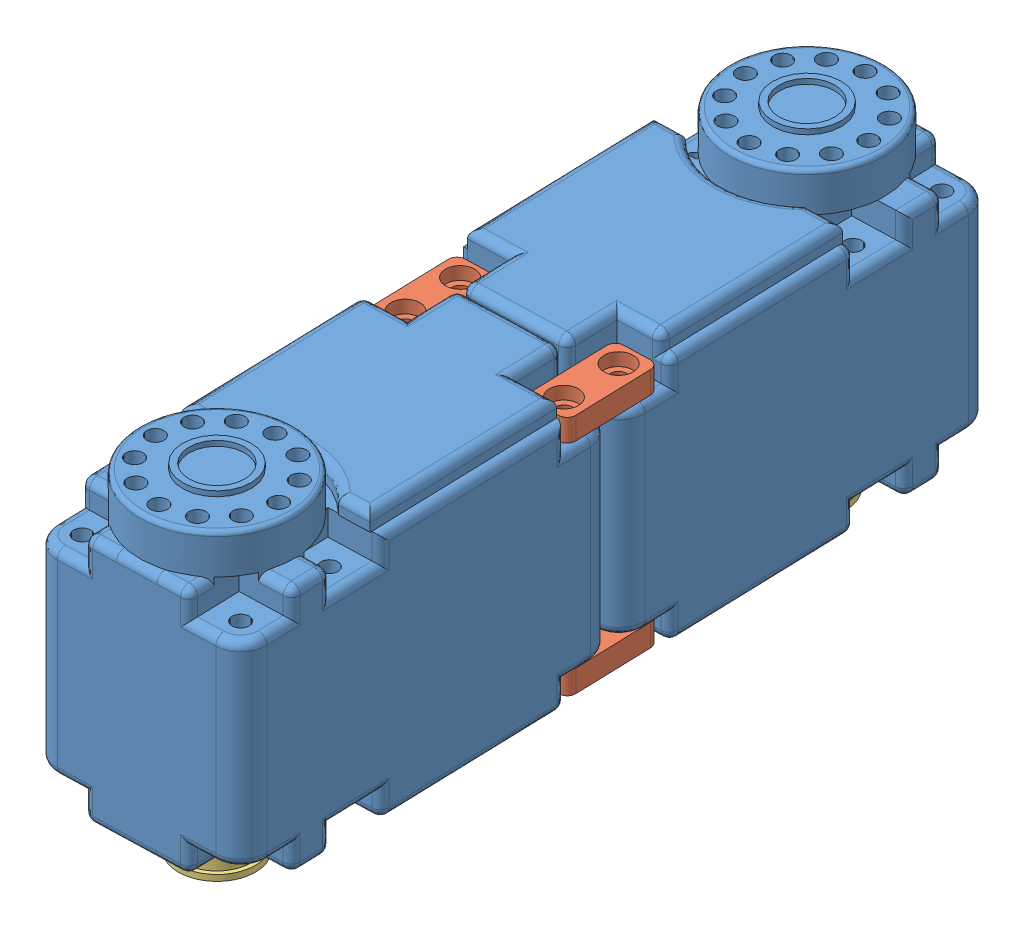
SolidWorks assembly arm, configuration Default. Lengths in mm.
Overall size (26.73 39.2 91.28).
8 component instances, 3 part files, 18 mates.
Components (placement in the parent):
- herkulex_motor-1: herkulex_motor [Default] at (3.1521 53.1425 38.0968) x (0.999543 0 -0.030221) z (0.030221 0 0.999543) size (24 34.2 45)
- line loint-1: line loint [Default] at (12.8371 53.5425 60.6144) x (-0.030221 0 -0.999543) z (0.999543 0 -0.030221) size (11 2.6 5)
- line loint-2: line loint [Default] at (-5.1547 53.5425 61.1584) x (-0.030221 0 -0.999543) z (0.999543 0 -0.030221) size (11 2.6 5)
- line loint-3: line loint [Default] at (12.8371 79.1425 60.6144) x (-0.030221 0 -0.999543) z (0.999543 0 -0.030221) size (11 2.6 5)
- line loint-4: line loint [Default] at (-5.1547 79.1425 61.1584) x (-0.030221 0 -0.999543) z (0.999543 0 -0.030221) size (11 2.6 5)
- support-1: support [Default] at (2.7653 53.6425 25.3027) x (0 -1 0) z (0 0 1) size (5.5 9 9)
- herkulex_motor-3: herkulex_motor [Default] at (4.5302 53.1425 83.676) x (-0.999543 0 0.030221) z (-0.030221 0 -0.999543) size (24 34.2 45)
- support-2: support [Default] at (4.917 53.6425 96.4701) x (0 -1 0) z (0 0 1) size (5.5 9 9)
Mates (geometry in assembly coordinates):
- Concentric1: concentric aligned: cylinder of herkulex_motor-1 through (12.7373 53.1425 57.3159) axis (0 1 0) radius 1; cylinder of line loint-1 through (12.7373 54.6425 57.3159) axis (0 1 0) radius 1.7
- Coincident4: coincident anti-aligned: plane of herkulex_motor-1 through (3.1521 56.1425 38.0968) normal (0 -1 0); plane of line loint-1 through (12.8371 56.1425 60.6144) normal (0 1 0)
- Concentric3: concentric anti-aligned: cylinder of herkulex_motor-1 through (-5.2545 53.1425 57.8599) axis (0 1 0) radius 1; cylinder of line loint-2 through (-5.2545 56.1425 57.8599) axis (0 -1 0) radius 1
- Coincident5: coincident anti-aligned: plane of herkulex_motor-1 through (3.1521 56.1425 38.0968) normal (0 -1 0); plane of line loint-2 through (-5.1547 56.1425 61.1584) normal (0 1 0)
- Concentric5: concentric aligned: cylinder of herkulex_motor-1 through (12.7373 53.1425 57.3159) axis (0 1 0) radius 1; cylinder of line loint-3 through (12.7373 80.2425 57.3159) axis (0 1 0) radius 1.7
- Coincident6: coincident anti-aligned: plane of herkulex_motor-1 through (3.1521 79.1425 38.0968) normal (0 1 0); plane of line loint-3 through (12.8371 79.1425 60.6144) normal (0 -1 0)
- Concentric7: concentric aligned: cylinder of herkulex_motor-1 through (-5.2545 53.1425 57.8599) axis (0 1 0) radius 1; cylinder of line loint-4 through (-5.2545 80.2425 57.8599) axis (0 1 0) radius 1.7
- Coincident7: coincident anti-aligned: plane of herkulex_motor-1 through (3.1521 79.1425 38.0968) normal (0 1 0); plane of line loint-4 through (-8.0335 79.1425 59.6395) normal (0 -1 0)
- Coincident8: coincident anti-aligned: plane of herkulex_motor-1 through (2.7653 53.6425 25.3027) normal (0 -1 0); plane of support-1 through (2.7653 53.6425 25.3027) normal (0 1 0)
- Concentric8: concentric aligned: circle of herkulex_motor-1; cylinder of support-1 through (2.7653 50.1425 25.3027) axis (0 -1 0) radius 2.7
- Concentric9: concentric aligned: cylinder of line loint-2 through (-5.055 54.6425 64.4569) axis (0 1 0) radius 1.7; cylinder of herkulex_motor-3 through (-5.055 53.1425 64.4569) axis (0 1 0) radius 1
- Coincident9: coincident anti-aligned: plane of line loint-2 through (-5.1547 56.1425 61.1584) normal (0 1 0); plane of herkulex_motor-3 through (4.5302 56.1425 83.676) normal (0 -1 0)
- Coincident10: coincident aligned: plane of herkulex_motor-1 through (-8.1624 84.1425 60.9492) normal (-0.999543 0 0.030221); plane of herkulex_motor-3 through (-8.1443 84.1425 61.5489) normal (-0.999543 0 0.030221)
- Parallel2: parallel aligned: plane of line loint-3 through (15.5021 81.7425 66.0364) normal (0.999543 0 -0.030221); plane of herkulex_motor-3 through (15.8447 84.1425 60.8236) normal (0.999543 0 -0.030221)
- Coincident12: coincident aligned: plane of line loint-1 through (15.5021 56.1425 66.0364) normal (0.999543 0 -0.030221); plane of line loint-3 through (15.5021 81.7425 66.0364) normal (0.999543 0 -0.030221)
- Coincident13: coincident aligned: plane of line loint-2 through (-7.4874 56.1425 66.7314) normal (-0.999543 0 0.030221); plane of line loint-4 through (-7.4874 81.7425 66.7314) normal (-0.999543 0 0.030221)
- Concentric10: concentric: cylinder of herkulex_motor-3 through (4.917 63.1425 96.4701) axis (0 -1 0) radius 1.475; cylinder of support-2 through (4.917 43.6425 96.4701) axis (0 1 0) radius 1.5
- Coincident14: coincident anti-aligned: plane of herkulex_motor-3 through (4.917 53.6425 96.4701) normal (0 -1 0); plane of support-2 through (4.917 53.6425 96.4701) normal (0 1 0)
